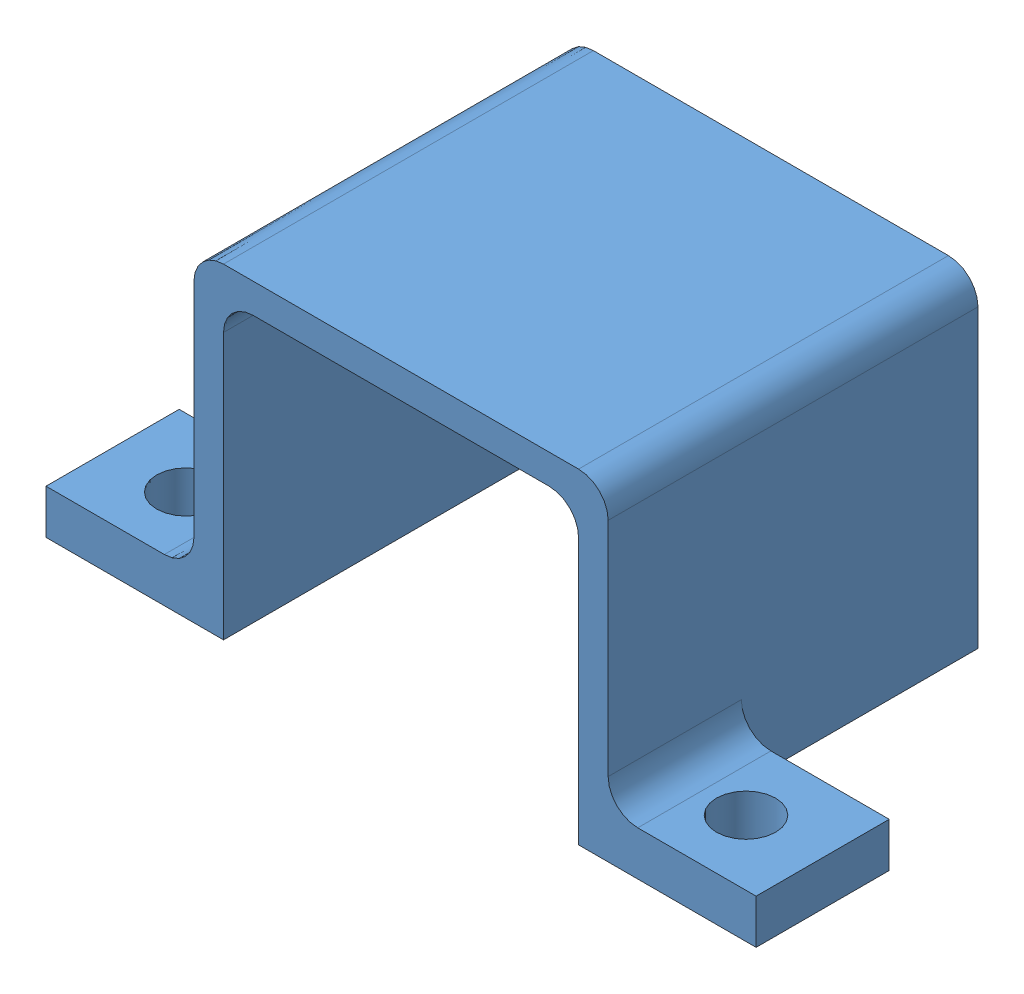
SolidWorks assembly motorAssem, configuration Default. Lengths in mm.
Overall size (24 11 12.5).
2 component instances, 2 part files, 0 mates.
Components (placement in the parent):
- micro-metal-gearmotor-1000.step-1: micro-metal-gearmotor-1000.step [Default] at (14.519 20.2221 27.5904) size (12 10.04 39.3) (hidden)
- MotorBracket-1: MotorBracket [Default] at origin size (24 11 12.5)
